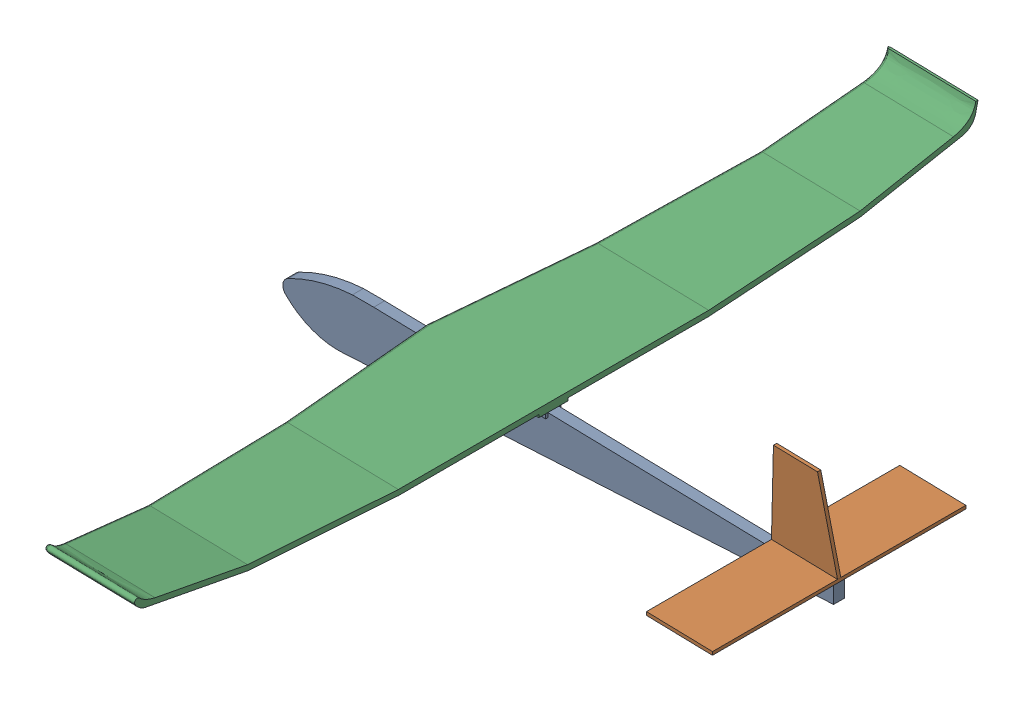
SolidWorks assembly assembly of glider 1, configuration Default. Lengths in mm.
Overall size (501.81 119.41 765.35).
3 component instances, 3 part files, 5 mates.
Components (placement in the parent):
- fuselage-1: fuselage [Default] at (-132.8439 20.0097 57.8579) size (499.94 50 14)
- stabalizer-1: stabalizer [Default] at (370.589 38.7273 62.8195) x (0 0 1) z (-0.023948 -0.999713 0) size (230 60 78)
- wing-1: wing [Default] at (141.3471 49.0619 -339.1536) x (-0.999713 0.023948 0) z (0 0 -1) size (115 57.87 765.35)
Mates (geometry in assembly coordinates):
- Coincident6: coincident anti-aligned: plane of fuselage-1 through (-132.1789 47.7703 57.8579) normal (0.023948 0.999713 0); plane of stabalizer-1 through (370.5171 35.7281 62.8195) normal (-0.023948 -0.999713 0)
- Coincident7: coincident aligned: line of fuselage-1 through (400.5085 35.0097 57.8579) axis (0 0 1); line of stabalizer-1 through (400.5085 35.0097 -52.1805) axis (0 0 1)
- Coincident11: coincident anti-aligned: plane of fuselage-1 through (26.0396 38.9787 60.3579) normal (0 0 1); plane of wing-1 through (26.3801 51.8159 60.3579) normal (0 0 -1)
- Coincident12: coincident anti-aligned: plane of fuselage-1 through (-132.2986 42.7717 57.8579) normal (0.023948 0.999713 0); plane of wing-1 through (26.0725 38.9779 -339.1536) normal (-0.023948 -0.999713 0)
- Coincident13: coincident anti-aligned: plane of fuselage-1 through (141.0396 36.2239 60.3579) normal (-0.999713 0.023948 0); plane of wing-1 through (141.3471 49.0619 -339.1536) normal (0.999713 -0.023948 0)
